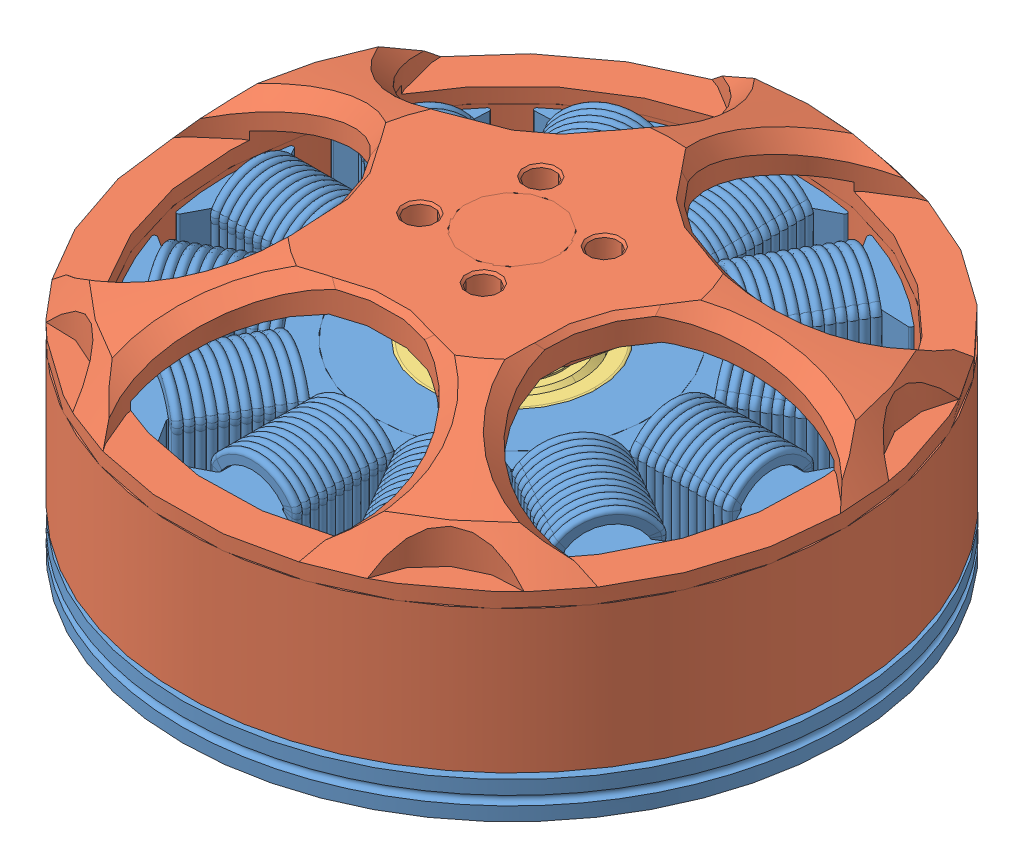
SolidWorks assembly Motor, configuration Default. Lengths in mm.
Overall size (72.67 40.86 72.89).
4 component instances, 3 part files, 6 mates.
Components (placement in the parent):
- Stator-1: Stator [Default] at (21.7415 20.5465 43.7841) size (57.88 23.73 57.88)
- Rotor-1: Rotor [Default] at (21.7415 29.0465 43.7841) x (-0.954761 0 -0.297375) z (0.297375 0 -0.954761) size (57.96 40.86 58.29)
- Motor Bearing-1: Motor Bearing [Default] at (21.7415 24.5484 43.7841) x (0 1 0) z (0 0 1) size (5 15.01 15.01)
- Motor Bearing-2: Motor Bearing [Default] at (21.7415 39.0446 43.7841) x (0 1 0) z (0 0 1) size (5 15.01 15.01)
Mates (geometry in assembly coordinates):
- Concentric1: concentric aligned: cylinder of Stator-1 through (21.7415 20.5465 43.7841) axis (0 -1 0) radius 28.94; cylinder of Rotor-1 through (21.7415 41.5465 43.7841) axis (0 -1 0) radius 28.94
- Distance1: distance = 29.36 mm anti-aligned: plane of Rotor-1 through (21.7415 49.9065 43.7841) normal (0 1 0); plane of Stator-1 through (21.7415 20.5465 43.7841) normal (0 -1 0)
- Concentric2: concentric anti-aligned: cylinder of Stator-1 through (21.7415 20.5465 43.7841) axis (0 -1 0) radius 7.5; cylinder of Motor Bearing-2 through (21.7415 36.2925 43.7841) axis (0 1 0) radius 7.5057
- Coincident2: coincident aligned: plane of Stator-1 through (21.7415 41.5465 43.7841) normal (0 1 0); plane of Motor Bearing-2 through (21.7415 41.5465 43.7841) normal (0 1 0)
- Concentric3: concentric anti-aligned: cylinder of Stator-1 through (21.7415 20.5465 43.7841) axis (0 -1 0) radius 7.5; cylinder of Motor Bearing-1 through (21.7415 21.7963 43.7841) axis (0 1 0) radius 7.5057
- Coincident3: coincident aligned: circle of Stator-1; plane of Motor Bearing-1 through (21.7415 22.0465 43.7841) normal (0 -1 0)
